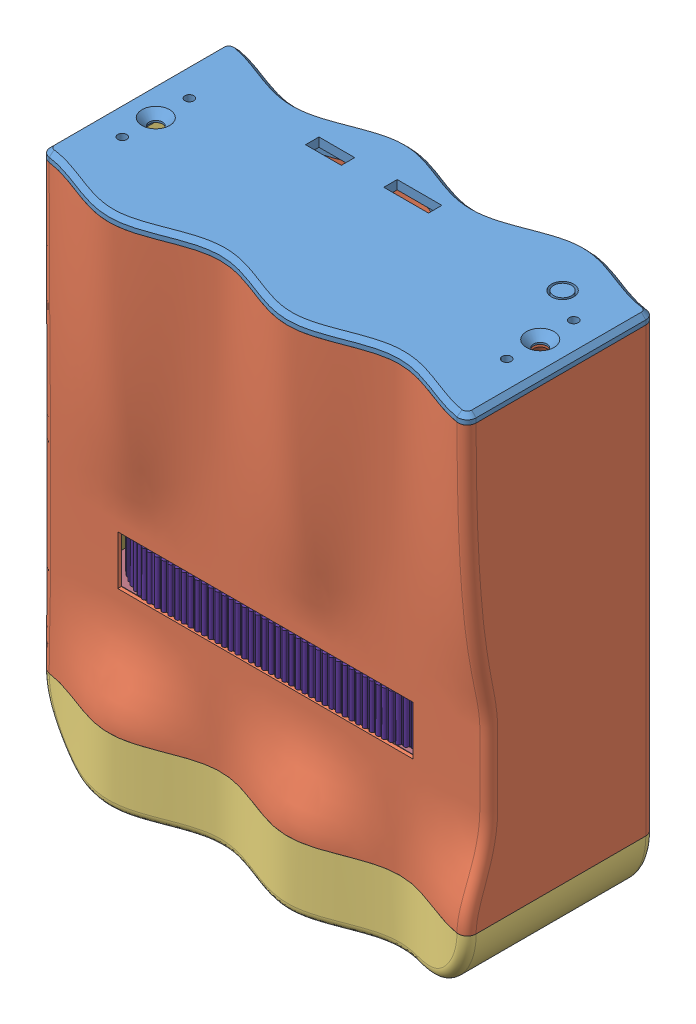
SolidWorks assembly Thenar_assembly, configuration Default. Lengths in mm.
Overall size (102.99 117.37 55.02).
35 component instances, 21 part files, 21 mates.
Components (placement in the parent):
- ThenarWave_case_bot-2: ThenarWave_case_bot [Default] at (-6.5655 -85.7911 148.1746) size (100 17 47.09)
- ThenarWave_case_wall-1: ThenarWave_case_wall [Default] at (-6.5655 -184.7911 148.1746) size (102.99 99.51 52.61)
- ThenarWave_case_top-2: ThenarWave_case_top [Default] at (-6.5655 -199.7911 148.1746) size (100 19.38 53.73)
- ThenarCell_case_assem-1: ThenarCell_case_assem [clean] at (-26.5139 -214.7272 173.8145) x (0 0 -1) z (1 0 0) size (30 32 75.62)
  - ThenarRelay_case-1: ThenarRelay_case [Default] at (10.6399 29.9361 89.9484) size (30 16 74.9)
  - ThenarNozzle0.1-1: ThenarNozzle0.1 [Default] at (21.1399 29.9361 22.9484) x (0 0 1) z (0 1 0) size (74.9 9 15)
  - ThenarRelay-1: ThenarRelay [Default] at (25.6399 31.2361 50.9484) size (14.5 14.2 18.3)
  - ThenarRelay-2: ThenarRelay [Default] at (25.6399 31.2361 69.9484) size (14.5 14.2 18.3)
  - ThenarRelay-3: ThenarRelay [Default] at (25.6399 30.9361 88.9484) size (14.5 14.2 18.3)
  - ThenarRelay-4: ThenarRelay [Default] at (11.1399 30.9361 50.9484) size (14.5 14.2 18.3)
  - ThenarRelay-5: ThenarRelay [Default] at (11.1399 30.9361 69.9484) size (14.5 14.2 18.3)
  - ThenarRelay-6: ThenarRelay [Default] at (11.1399 30.9361 88.9484) size (14.5 14.2 18.3)
  - ThenarString1-1: ThenarString1 [Default] at (32.2248 42.9361 35.3129) x (-0.305377 0 0.952232) z (0 1 0) size (18.87 1.4 29)
  - ThenarString1-2: ThenarString1 [Default] at (18.6263 42.9361 73.4402) x (0.329914 0 -0.944011) z (0 1 0) size (18.87 1.4 29)
  - ThenarString1-3: ThenarString1 [Default] at (18.5639 42.9361 35.4784) x (0.333482 0 0.942757) z (0 1 0) size (18.87 1.4 29)
  - ThenarString1-4: ThenarString1 [Default] at (32.6823 42.9361 73.4301) x (-0.331564 0 -0.943433) z (0 1 0) size (18.87 1.4 29)
  - ThenarString2-1: ThenarString2 [Default] at (18.6399 42.9361 54.4484) x (1 0 0) z (0 1 0) size (7.15 1.4 29)
  - ThenarString2-2: ThenarString2 [Default] at (32.6399 42.9361 54.4484) x (-1 0 0) z (0 1 0) size (7.15 1.4 29)
  - ThenarM3-1: ThenarM3 [Default] at (25.6399 28.1361 27.4484) x (0.146051 0 0.989277) z (-0.989277 0 0.146051) size (5.32 6 5.32)
  - ThenarM3-2: ThenarM3 [Default] at (25.6399 28.1361 94.4484) x (-0.949881 0 0.312612) z (-0.312612 0 -0.949881) size (5.32 6 5.32)
  - ThenarM3_Nut-1: ThenarM3_Nut [Default] at (25.6399 31.4361 27.4484) x (-0.5 0 -0.866025) z (0.866025 0 -0.5) size (6.35 2.5 5.5)
  - ThenarM3_Nut-2: ThenarM3_Nut [Default] at (25.6399 31.4361 94.4484) x (0.5 0 -0.866025) z (0.866025 0 0.5) size (6.35 2.5 5.5)
- ThenarI-frame-1: ThenarI-frame [Default] at (85.3345 -86.2911 144.1746) x (0 0 1) z (0 1 0) size (14.4 8.3 105)
- ThenarY-frame-1: ThenarY-frame [Default] at (-1.2655 -86.2911 144.1746) x (0 0 1) z (0 1 0) size (27 7 105)
- ThenarJogger_assem-1: ThenarJogger_assem [Default] at (10.3198 -201.4986 74.188) size (87.48 59.66 39.57)
  - ThenarJogger_frame_1-1: ThenarJogger_frame_1 [Default] at (8.1147 38.7075 77.5867) size (80 15 30)
  - ThenarBlock_28-1: ThenarBlock_28 [Default] at (8.1147 40.7075 77.5867) x (-0.731206 0 0.682157) z (-0.682157 0 -0.731206) size (28 10 28)
  - ThenarBlock_28-2: ThenarBlock_28 [Default] at (58.1147 40.7075 77.5867) x (0.949356 0 0.314202) z (-0.314202 0 0.949356) size (28 10 28)
  - ThenarJogger_frame_2-1: ThenarJogger_frame_2 [Default] at (58.1147 53.7075 77.5867) x (-1 0 0) z (0 0 1) size (80 11 30)
  - ThenarGT2-20-1: ThenarGT2-20 [Default] at (42.3991 35.7075 68.1515) x (0 1 0) z (-0.417797 0 0.90854) size (10 12.02 12.02)
  - ThenarJogger_belt-1: ThenarJogger_belt [Default] at (8.1147 41.2075 77.5867) size (80 10 30)
  - ThenarEncoder-1: ThenarEncoder [Default] at (27.1147 65.2075 77.5867) x (0 0 -1) z (-1 0 0) size (12 26.5 12)
- ThenarButton-1: ThenarButton [Default] at (75.9345 -93.7911 139.6746) size (7 10 7)
- Thenar18650-1: Thenar18650 [Default] at (76.4345 -95.7911 150.1746) x (0 0.091581 0.995798) z (-1 0 0) size (18.5 18.5 65.5)
- ThenarDeck-1: ThenarDeck [Default] at (85.3345 -137.7911 164.7746) x (0 0 -1) z (1 0 0) size (20.6 33 83.8)
Mates (geometry in assembly coordinates):
- Concentric1: concentric aligned: cylinder of Wave_case_bot-2 through (91.4345 -84.7911 131.549) axis (0 -1 0) radius 2; cylinder of Wave_case_wall-1 through (91.4345 -135.2911 131.549) axis (0 -1 0) radius 2
- Coincident1: coincident anti-aligned: line of Wave_case_bot-2 through (-5.7655 -85.7911 163.7764) axis (0 0 -1); line of Wave_case_wall-1 through (-5.7655 -85.7911 126.8383) axis (0 0 1)
- Distance2: distance = 0.5 mm: line of Wave_case_top-2 through (20.4345 -199.7911 143.1746) axis (1 0 0); plane of Cell_case_assem-1/Nozzle0.1-1 through (-3.5655 -184.7911 143.6746) normal (0 0 -1)
- Coincident12: coincident: plane of Wave_case_top-2 through (43.4345 -199.7911 169.1746) normal (0 -1 0); line of Cell_case_assem-1/Nozzle0.1-1 through (20.9345 -199.7911 143.6746) axis (0 0 1)
- Distance3: distance = 0.5 mm anti-aligned: plane of Cell_case_assem-1/Nozzle0.1-1 through (20.9345 -199.7911 143.6746) normal (-1 0 0); plane of Wave_case_top-2 through (20.4345 -181.779 153.1746) normal (1 0 0)
- Coincident14: coincident aligned: line of Wave_case_wall-1 through (93.4345 -184.7911 169.511) axis (0 0 -1); line of Wave_case_top-2 through (93.4345 -184.7911 169.511) axis (0 0 -1)
- Coincident15: coincident anti-aligned: cylinder of Wave_case_wall-1 through (-4.5655 -135.2911 126.8383) axis (0 -1 0) radius 2; circle of Wave_case_top-2
- Parallel1: parallel anti-aligned: plane of Wave_case_bot-2 through (43.4345 -85.7911 169.1746) normal (0 -1 0); plane of I-frame-1 through (88.1345 -86.2911 152.1746) normal (0 1 0)
- Coincident21: coincident anti-aligned: circle of Wave_case_top-2; circle of I-frame-1
- Coincident23: coincident aligned: circle of Wave_case_top-2; circle of Y-frame-1
- Parallel4: parallel: plane of assembly; plane of ThenarWave_case_bot-2 through (43.4345 -85.7911 169.1746) normal (0 -1 0); plane of ThenarY-frame-1 through (1.5345 -86.2911 152.1746) normal (0 1 0)
- Distance4: distance = 8.4 mm aligned: plane of Jogger_assem-1/Jogger_frame_1-1 through (3.4345 -160.7911 135.7746) normal (0 0 -1); plane of Y-frame-1 through (1.5345 -86.2911 144.1746) normal (0 0 -1)
- Coincident27: coincident aligned: plane of Wave_case_wall-1 through (10.4345 -149.7911 123.7152) normal (0 -1 0); plane of Jogger_assem-1/Jogger_frame_2-1 through (68.4345 -149.7911 151.7746) normal (0 -1 0)
- Distance6: distance = 10 mm aligned: plane of Jogger_assem-1/Jogger_frame_1-1 through (3.4345 -160.7911 165.7746) normal (-1 0 0); plane of Wave_case_wall-1 through (-6.5655 -85.7911 166.6746) normal (-1 0 0)
- Concentric3: concentric aligned: cylinder of Wave_case_bot-2 through (79.4345 -83.7896 136.1746) axis (0 -1 0) radius 2.5; cylinder of Button-1 through (79.4345 -83.7911 136.1746) axis (0 -1 0) radius 2
- Coincident29: coincident aligned: plane of Wave_case_bot-2 through (43.4345 -83.7911 169.1746) normal (0 1 0); plane of Button-1 through (79.4345 -83.7911 136.1746) normal (0 1 0)
- Concentric4: concentric anti-aligned: cylinder of Wave_case_bot-2 through (103.8483 -95.7911 150.1746) axis (-1 0 0) radius 9; cylinder of 18650-1 through (10.9345 -95.7911 150.1746) axis (1 0 0) radius 9.25
- Distance7: distance = 2 mm anti-aligned: plane of 18650-1 through (76.4345 -95.7911 150.1746) normal (1 0 0); plane of Wave_case_bot-2 through (78.4345 -98.7911 155.1746) normal (-1 0 0)
- Concentric6: concentric aligned: circle of I-frame-1; circle of Deck-1
- Coincident31: coincident anti-aligned: plane of I-frame-1 through (85.3345 -86.2911 144.1746) normal (-1 0 0); plane of Deck-1 through (85.3345 -137.7911 164.1746) normal (1 0 0)
- Parallel5: parallel aligned: plane of Y-frame-1 through (1.5345 -86.2911 144.1746) normal (0 0 -1); plane of Deck-1 through (85.3345 -137.7911 164.1746) normal (0 0 -1)
